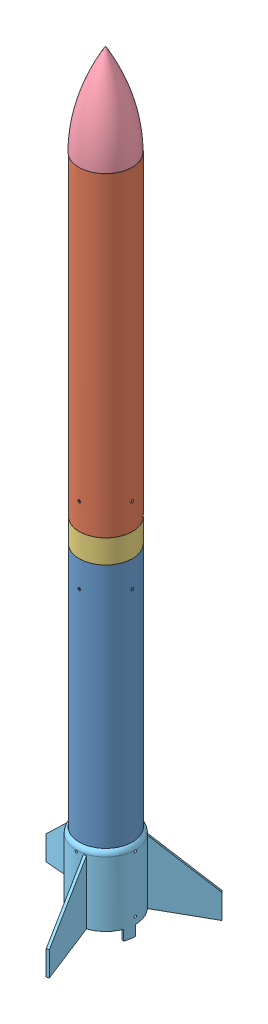
SolidWorks assembly rocket v1 for stl display, configuration Default. Lengths in mm.
Overall size (200.74 1096.45 200.74).
5 component instances, 5 part files, 8 mates.
Components (placement in the parent):
- body tube bottom-1: body tube bottom [Default] at (240.8778 40.28 293.3102) size (77 457.2 77)
- body tube top-1: body tube top [Default] at (240.8778 531.48 293.3102) size (77 457.2 77)
- coupler-1: coupler [Default] at (240.8778 438.28 293.3102) x (0.999495 0 -0.031765) z (0.031765 0 0.999495) size (77 152.4 77)
- nosecone-1: nosecone [Default] at (240.4554 1125.1317 293.327) x (0 -1 0) z (0.039735 0 0.99921) size (158.05 77 77)
- rocketPadConnectorTop-1: rocketPadConnectorTop [Default] at (240.8778 40.28 293.3102) size (200.74 116.6 200.74)
Mates (geometry in assembly coordinates):
- Concentric1: concentric aligned: cylinder of body tube bottom-1 through (240.8778 497.48 293.3102) axis (0 -1 0) radius 36.5; cylinder of coupler-1 through (240.8778 590.68 293.3102) axis (0 -1 0) radius 38
- Concentric2: concentric aligned: cylinder of body tube top-1 through (240.8778 988.68 293.3102) axis (0 -1 0) radius 36.5; cylinder of coupler-1 through (240.8778 590.68 293.3102) axis (0 -1 0) radius 38
- Concentric3: concentric anti-aligned: cylinder of body tube top-1 through (240.8778 988.68 293.3102) axis (0 -1 0) radius 36.5; cylinder of nosecone-1 through (240.8778 963.68 293.3102) axis (0 1 0) radius 36.875
- Coincident2: coincident anti-aligned: circle of body tube top-1; plane of nosecone-1 through (240.4554 988.68 293.327) normal (0 -1 0)
- Coincident3: coincident aligned: circle of body tube top-1; circle of coupler-1
- Coincident4: coincident aligned: circle of body tube bottom-1; circle of coupler-1
- Concentric4: concentric: cylinder of body tube bottom-1 through (240.8778 497.48 293.3102) axis (0 -1 0) radius 38.5; cylinder of rocketPadConnectorTop-1 through (240.8778 141.88 293.3102) axis (0 -1 0) radius 38.75
- Coincident5: coincident anti-aligned: circle of body tube bottom-1; plane of rocketPadConnectorTop-1 through (240.8778 40.28 293.3102) normal (0 -1 0)
